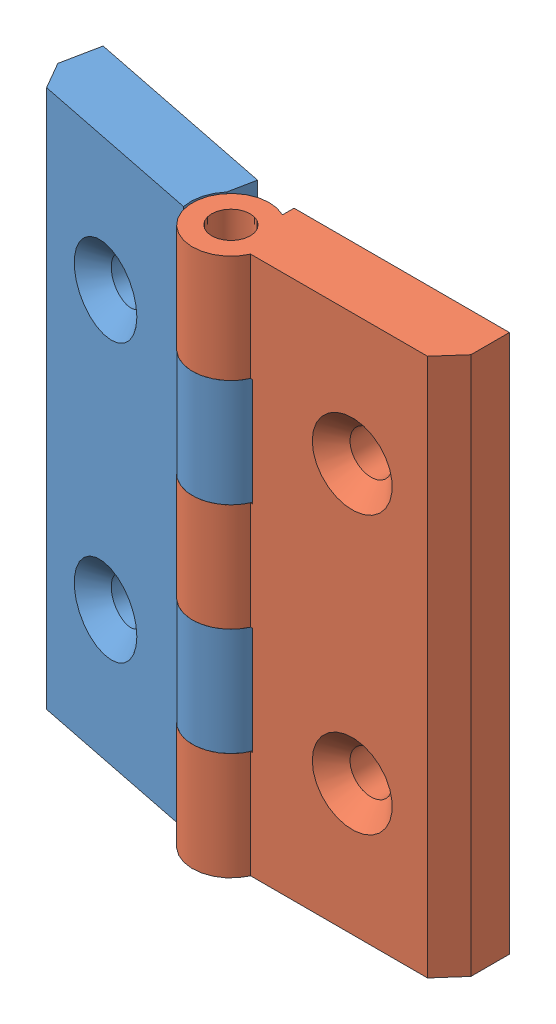
SolidWorks assembly HQ metal enclosure HINGE, configuration Default. Lengths in mm.
Overall size (60.83 70 17.71).
2 component instances, 2 part files, 2 mates.
Components (placement in the parent):
- enclosure HINGE2-1: enclosure HINGE2 [Default] at (-4.8244 -7.0126 6.241) x (0.980346 0 0.197285) z (-0.197285 0 0.980346) size (35.22 70 10.98)
- enclosure HINGE1-1: enclosure HINGE1 [Default] at (53.8412 -7.0126 12.0853) x (-1 0 0) z (0 0 1) size (35.22 70 10.98)
Mates (geometry in assembly coordinates):
- Concentric1: concentric anti-aligned: cylinder of enclosure HINGE2-1 through (23.6215 27.9874 18.0656) axis (0 -1 0) radius 2.5; cylinder of enclosure HINGE1-1 through (23.6215 -42.0126 18.0656) axis (0 1 0) radius 2.5
- Coincident1: coincident anti-aligned: plane of enclosure HINGE2-1 through (36.9226 13.9874 25.8426) normal (0 1 0); plane of enclosure HINGE1-1 through (9.0476 13.9874 23.0656) normal (0 -1 0)
